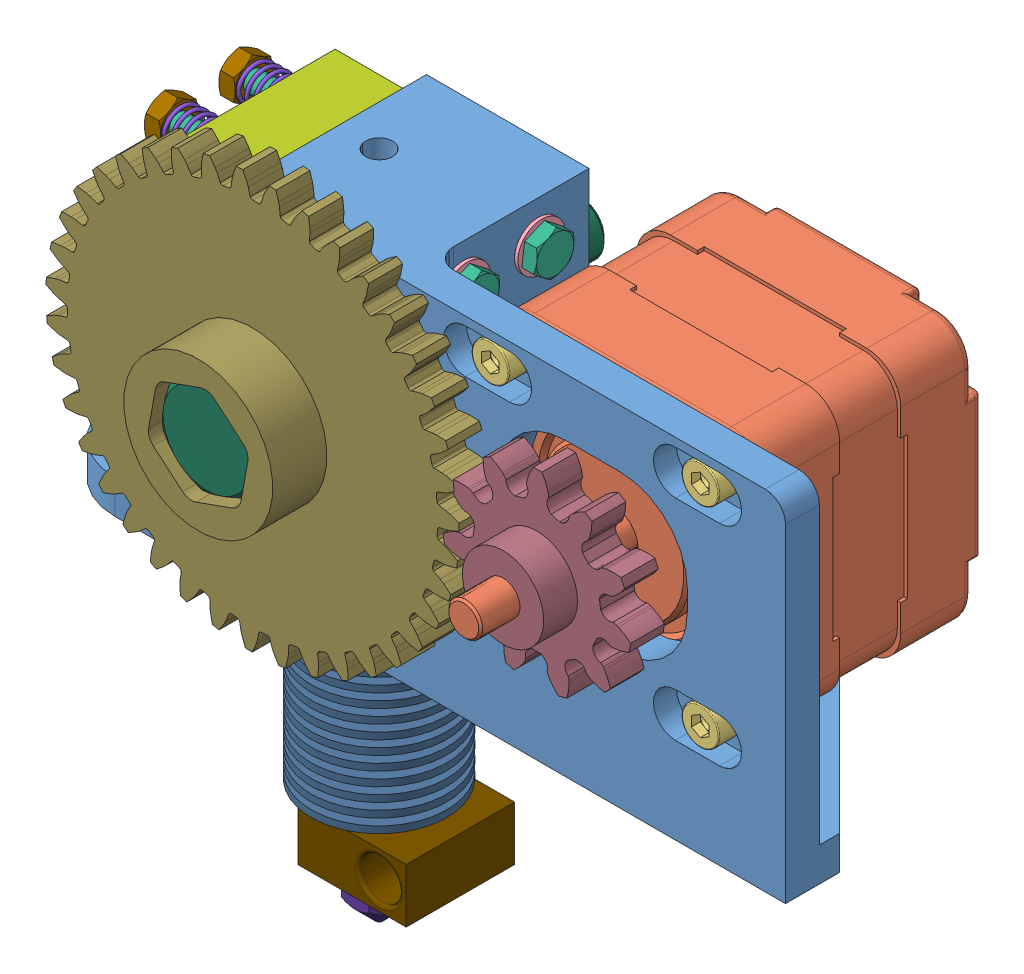
SolidWorks assembly X-Chariot, configuration Défaut. Lengths in mm.
Overall size (113.48 121.48 59.4).
80 component instances, 20 part files, 9 mates.
Components (placement in the parent):
- Extruder Body-1: Extruder Body [Défaut] at (51.5422 19.5906 0.8363) x (-1 0 0) z (0 0 -1) size (109 51.5 28)
- plain washer grade a_din_Washer DIN 125 - A 3.7-1: plain washer grade a_din_Washer DIN 125 - A 3.7 [Défaut] at (-44.9578 19.5906 7.8363) x (0 -1 0) z (0 0 1) size (0.5 8 8) (hidden)
- plain washer grade a_din_Washer DIN 125 - A 3.7-2: plain washer grade a_din_Washer DIN 125 - A 3.7 [Défaut] at (-44.9578 19.5906 21.8363) x (0 -1 0) z (0 0 1) size (0.5 8 8) (hidden)
- plain washer grade a_din_Washer DIN 125 - A 3.7-3: plain washer grade a_din_Washer DIN 125 - A 3.7 [Défaut] at (16.0422 19.5906 6.5863) x (0 -1 0) z (0 0 1) size (0.5 8 8) (hidden)
- plain washer grade a_din_Washer DIN 125 - A 3.7-4: plain washer grade a_din_Washer DIN 125 - A 3.7 [Défaut] at (16.0422 19.5906 18.0863) x (0 -1 0) z (0 0 1) size (0.5 8 8) (hidden)
- plain washer grade a_din_Washer DIN 125 - A 3.7-5: plain washer grade a_din_Washer DIN 125 - A 3.7 [Défaut] at (16.0422 3.5906 6.5863) x (0 1 0) z (0 0 1) size (0.5 8 8) (hidden)
- plain washer grade a_din_Washer DIN 125 - A 3.7-6: plain washer grade a_din_Washer DIN 125 - A 3.7 [Défaut] at (16.0422 3.5906 18.0863) x (0 1 0) z (0 0 1) size (0.5 8 8) (hidden)
- plain washer grade a_din_Washer DIN 125 - A 3.7-7: plain washer grade a_din_Washer DIN 125 - A 3.7 [Défaut] at (-44.9578 3.5906 7.8363) x (0 1 0) z (0 0 1) size (0.5 8 8) (hidden)
- plain washer grade a_din_Washer DIN 125 - A 3.7-8: plain washer grade a_din_Washer DIN 125 - A 3.7 [Défaut] at (-44.9578 3.5906 21.8363) x (0 1 0) z (0 0 1) size (0.5 8 8) (hidden)
- hex bolt gradeb_iso_ISO 4015 - M3 x 20 x 20-C-1: hex bolt gradeb_iso_ISO 4015 - M3 x 20 x 20-C [Défaut] at (-44.9578 22.0906 21.8363) x (0 -1 0) z (0 0 1) size (22 6.35 5.5) (hidden)
- hex bolt gradeb_iso_ISO 4015 - M3 x 20 x 20-C-2: hex bolt gradeb_iso_ISO 4015 - M3 x 20 x 20-C [Défaut] at (-44.9578 22.0906 7.8363) x (0 -1 0) z (0 0 1) size (22 6.35 5.5) (hidden)
- hex bolt gradeb_iso_ISO 4015 - M3 x 20 x 20-C-3: hex bolt gradeb_iso_ISO 4015 - M3 x 20 x 20-C [Défaut] at (16.0422 22.0906 6.5863) x (0 -1 0) z (0 0 1) size (22 6.35 5.5) (hidden)
- hex bolt gradeb_iso_ISO 4015 - M3 x 20 x 20-C-4: hex bolt gradeb_iso_ISO 4015 - M3 x 20 x 20-C [Défaut] at (16.0422 22.0906 18.0863) x (0 -1 0) z (0 0 1) size (22 6.35 5.5) (hidden)
- hex nut style 1 gradeab_iso_Hexagon Nut ISO - 4032 - M3 - D - C-1: hex nut style 1 gradeab_iso_Hexagon Nut ISO - 4032 - M3 - D - C [Défaut] at (-44.9578 0.6906 21.8363) x (1 0 0) z (0 -1 0) size (5.5 6.35 2.4) (hidden)
- hex nut style 1 gradeab_iso_Hexagon Nut ISO - 4032 - M3 - D - C-2: hex nut style 1 gradeab_iso_Hexagon Nut ISO - 4032 - M3 - D - C [Défaut] at (-44.9578 0.6906 7.8363) x (1 0 0) z (0 -1 0) size (5.5 6.35 2.4) (hidden)
- hex nut style 1 gradeab_iso_Hexagon Nut ISO - 4032 - M3 - D - C-3: hex nut style 1 gradeab_iso_Hexagon Nut ISO - 4032 - M3 - D - C [Défaut] at (16.0422 0.6906 6.5863) x (1 0 0) z (0 -1 0) size (5.5 6.35 2.4) (hidden)
- hex nut style 1 gradeab_iso_Hexagon Nut ISO - 4032 - M3 - D - C-4: hex nut style 1 gradeab_iso_Hexagon Nut ISO - 4032 - M3 - D - C [Défaut] at (16.0422 0.6906 18.0863) x (1 0 0) z (0 -1 0) size (5.5 6.35 2.4) (hidden)
- NEMA 17 Bipolar Stepper Motor-1: NEMA 17 Bipolar Stepper Motor [Défaut] at (23.0422 46.0906 7.3363) x (0 0 1) z (-1 0 0) size (57.01 39.01 39.01)
- socket head cap screw_iso_ISO 4762 M3 x 5 --- 5C-1: socket head cap screw_iso_ISO 4762 M3 x 5 --- 5C [Défaut] at (7.5422 61.5906 28.4363) x (0 0 -1) z (1 0 0) size (8 5.5 5.5)
- socket head cap screw_iso_ISO 4762 M3 x 5 --- 5C-2: socket head cap screw_iso_ISO 4762 M3 x 5 --- 5C [Défaut] at (38.5422 61.5906 28.4363) x (0 0 -1) z (1 0 0) size (8 5.5 5.5)
- socket head cap screw_iso_ISO 4762 M3 x 5 --- 5C-3: socket head cap screw_iso_ISO 4762 M3 x 5 --- 5C [Défaut] at (7.5422 30.5906 28.4363) x (0 0 -1) z (1 0 0) size (8 5.5 5.5)
- socket head cap screw_iso_ISO 4762 M3 x 5 --- 5C-4: socket head cap screw_iso_ISO 4762 M3 x 5 --- 5C [Défaut] at (38.5422 30.5906 28.4363) x (0 0 -1) z (1 0 0) size (8 5.5 5.5)
- plain washer grade a_din_Washer DIN 125 - A 3.2-1: plain washer grade a_din_Washer DIN 125 - A 3.2 [Défaut] at (-29.4578 60.0906 8.3363) size (0.5 7 7)
- plain washer grade a_din_Washer DIN 125 - A 3.2-2: plain washer grade a_din_Washer DIN 125 - A 3.2 [Défaut] at (-29.9578 60.0906 8.3363) size (0.5 7 7)
- plain washer grade a_din_Washer DIN 125 - A 3.2-3: plain washer grade a_din_Washer DIN 125 - A 3.2 [Défaut] at (-30.4578 60.0906 8.3363) size (0.5 7 7)
- plain washer grade a_din_Washer DIN 125 - A 3.2-4: plain washer grade a_din_Washer DIN 125 - A 3.2 [Défaut] at (-30.9578 60.0906 8.3363) x (1 0 0) z (0 0.451194 0.892426) size (0.5 7 7)
- Smooth Rod - f8x23-1: Smooth Rod - f8x23 [Défaut] at (-34.4578 46.0906 2.3363) x (1 0 0) z (0 -1 0) size (8 23 8)
- plain washer grade a_din_Washer DIN 125 - A 3.2-5: plain washer grade a_din_Washer DIN 125 - A 3.2 [Défaut] at (-5.4578 60.0906 19.3363) x (-1 0 0) z (0 0.924225 0.381849) size (0.5 7 7)
- plain washer grade a_din_Washer DIN 125 - A 3.2-6: plain washer grade a_din_Washer DIN 125 - A 3.2 [Défaut] at (-5.4578 60.0906 8.3363) x (-1 0 0) z (0 0.924225 0.381849) size (0.5 7 7)
- plain washer grade a_din_Washer DIN 125 - A 3.2-7: plain washer grade a_din_Washer DIN 125 - A 3.2 [Défaut] at (-5.4578 32.0906 8.3363) x (-1 0 0) z (0 0.924225 0.381849) size (0.5 7 7)
- plain washer grade a_din_Washer DIN 125 - A 3.2-8: plain washer grade a_din_Washer DIN 125 - A 3.2 [Défaut] at (-5.4578 32.0906 19.3363) x (-1 0 0) z (0 0.924225 0.381849) size (0.5 7 7)
- plain washer grade a_din_Washer DIN 125 - A 3.2-9: plain washer grade a_din_Washer DIN 125 - A 3.2 [Défaut] at (-29.4578 60.0906 19.3363) size (0.5 7 7)
- plain washer grade a_din_Washer DIN 125 - A 3.2-10: plain washer grade a_din_Washer DIN 125 - A 3.2 [Défaut] at (-29.4578 32.0906 19.3363) size (0.5 7 7)
- plain washer grade a_din_Washer DIN 125 - A 3.2-11: plain washer grade a_din_Washer DIN 125 - A 3.2 [Défaut] at (-29.4578 32.0906 8.3363) size (0.5 7 7)
- plain washer grade a_din_Washer DIN 125 - A 3.2-12: plain washer grade a_din_Washer DIN 125 - A 3.2 [Défaut] at (-29.9578 60.0906 19.3363) size (0.5 7 7)
- plain washer grade a_din_Washer DIN 125 - A 3.2-13: plain washer grade a_din_Washer DIN 125 - A 3.2 [Défaut] at (-30.4578 60.0906 19.3363) size (0.5 7 7)
- plain washer grade a_din_Washer DIN 125 - A 3.2-14: plain washer grade a_din_Washer DIN 125 - A 3.2 [Défaut] at (-29.9578 32.0906 19.3363) size (0.5 7 7)
- plain washer grade a_din_Washer DIN 125 - A 3.2-15: plain washer grade a_din_Washer DIN 125 - A 3.2 [Défaut] at (-30.4578 32.0906 19.3363) size (0.5 7 7)
- plain washer grade a_din_Washer DIN 125 - A 3.2-16: plain washer grade a_din_Washer DIN 125 - A 3.2 [Défaut] at (-30.9578 32.0906 19.3363) size (0.5 7 7)
- plain washer grade a_din_Washer DIN 125 - A 3.2-17: plain washer grade a_din_Washer DIN 125 - A 3.2 [Défaut] at (-29.9578 32.0906 8.3363) size (0.5 7 7)
- plain washer grade a_din_Washer DIN 125 - A 3.2-18: plain washer grade a_din_Washer DIN 125 - A 3.2 [Défaut] at (-30.4578 32.0906 8.3363) size (0.5 7 7)
- plain washer grade a_din_Washer DIN 125 - A 3.2-19: plain washer grade a_din_Washer DIN 125 - A 3.2 [Défaut] at (-30.9578 32.0906 8.3363) size (0.5 7 7)
- M3x45_ISO 4015 - M3 x 45 x 12-C-1: M3x45_ISO 4015 - M3 x 45 x 12-C [Défaut] at (-2.9578 60.0906 19.3363) x (-1 0 0) z (0 -0.924225 -0.381849) size (47 6.35 5.5)
- M3x45_ISO 4015 - M3 x 45 x 12-C-2: M3x45_ISO 4015 - M3 x 45 x 12-C [Défaut] at (-2.9578 32.0906 8.3363) x (-1 0 0) z (0 -0.924225 -0.381849) size (47 6.35 5.5)
- M3x45_ISO 4015 - M3 x 45 x 12-C-3: M3x45_ISO 4015 - M3 x 45 x 12-C [Défaut] at (-2.9578 32.0906 19.3363) x (-1 0 0) z (0 -0.924225 -0.381849) size (47 6.35 5.5)
- M3x45_ISO 4015 - M3 x 45 x 12-C-4: M3x45_ISO 4015 - M3 x 45 x 12-C [Défaut] at (-2.9578 60.0906 8.3363) x (-1 0 0) z (0 -0.924225 -0.381849) size (47 6.35 5.5)
- Idler Body-1: Idler Body [Défaut] at (-41.4578 28.0906 25.3363) x (0 0 -1) z (1 0 0) size (23 36 10)
- plain washer grade a_din_Washer DIN 125 - A 3.2-20: plain washer grade a_din_Washer DIN 125 - A 3.2 [Défaut] at (-30.9578 60.0906 19.3363) size (0.5 7 7)
- plain washer grade a_din_Washer DIN 125 - A 3.2-21: plain washer grade a_din_Washer DIN 125 - A 3.2 [Défaut] at (-41.4578 60.0906 8.3363) x (1 0 0) z (0 -0.022823 0.99974) size (0.5 7 7)
- plain washer grade a_din_Washer DIN 125 - A 3.2-22: plain washer grade a_din_Washer DIN 125 - A 3.2 [Défaut] at (-41.4578 60.0906 19.3363) size (0.5 7 7)
- plain washer grade a_din_Washer DIN 125 - A 3.2-23: plain washer grade a_din_Washer DIN 125 - A 3.2 [Défaut] at (-41.4578 32.0906 19.3363) size (0.5 7 7)
- plain washer grade a_din_Washer DIN 125 - A 3.2-24: plain washer grade a_din_Washer DIN 125 - A 3.2 [Défaut] at (-41.4578 32.0906 8.3363) size (0.5 7 7)
- Ballpoint Pen Spring - Extruder-1: Ballpoint Pen Spring - Extruder [Défaut] at (-42.2078 60.0906 8.3363) x (0 0.991476 -0.130286) z (0 0.130286 0.991476) size (5.53 5.52 5.5)
- Ballpoint Pen Spring - Extruder-2: Ballpoint Pen Spring - Extruder [Défaut] at (-42.2078 60.0906 19.3363) x (0 0.999694 0.024727) z (0 -0.024727 0.999694) size (5.53 5.52 5.5)
- Ballpoint Pen Spring - Extruder-3: Ballpoint Pen Spring - Extruder [Défaut] at (-42.2078 32.0906 8.3363) x (0 0.999047 -0.043643) z (0 0.043643 0.999047) size (5.53 5.52 5.5)
- Ballpoint Pen Spring - Extruder-4: Ballpoint Pen Spring - Extruder [Défaut] at (-42.2078 32.0906 19.3363) x (0 0.978843 -0.20461) z (0 0.20461 0.978843) size (5.53 5.52 5.5)
- hex nut style 1 gradeab_iso_Hexagon Nut ISO - 4032 - M3 - D - C-5: hex nut style 1 gradeab_iso_Hexagon Nut ISO - 4032 - M3 - D - C [Défaut] at (-47.4578 60.0906 8.3363) x (0 0 -1) z (1 0 0) size (5.5 6.35 2.4)
- hex nut style 1 gradeab_iso_Hexagon Nut ISO - 4032 - M3 - D - C-6: hex nut style 1 gradeab_iso_Hexagon Nut ISO - 4032 - M3 - D - C [Défaut] at (-47.4578 60.0906 19.3363) x (0 0 -1) z (1 0 0) size (5.5 6.35 2.4)
- hex nut style 1 gradeab_iso_Hexagon Nut ISO - 4032 - M3 - D - C-7: hex nut style 1 gradeab_iso_Hexagon Nut ISO - 4032 - M3 - D - C [Défaut] at (-46.9578 32.0906 8.3363) x (0 0.019138 -0.999817) z (1 0 0) size (5.5 6.35 2.4)
- hex nut style 1 gradeab_iso_Hexagon Nut ISO - 4032 - M3 - D - C-8: hex nut style 1 gradeab_iso_Hexagon Nut ISO - 4032 - M3 - D - C [Défaut] at (-47.4578 32.0906 19.3363) x (0 0.048448 -0.998826) z (1 0 0) size (5.5 6.35 2.4)
- Fourreau-1: Fourreau [Défaut] at (-23.4578 24.5906 13.8363) x (-1 0 0) z (0 0 -1) size (20 44 20)
- plain washer grade a_din_Washer DIN 125 - A 8.4-1: plain washer grade a_din_Washer DIN 125 - A 8.4 [Défaut] at (-18.9578 46.0906 28.8363) x (0 0 -1) z (0.999888 -0.014961 0) size (1.6 16 16)
- Large Gear-1: Large Gear [Défaut] at (-47.7391 12.1511 32.0363) x (-0.64677 -0.762685 0) z (0 0 1) size (60.98 60.94 13)
- plain washer grade a_din_Washer DIN 125 - A 8.4-2: plain washer grade a_din_Washer DIN 125 - A 8.4 [Défaut] at (-18.9578 46.0906 -0.7637) x (0 0 -1) z (0.808623 0.588327 0) size (1.6 16 16)
- Motor Shaft Pulley - Extruder-1: Motor Shaft Pulley - Extruder [Défaut] at (5.4114 54.4147 32.0363) x (0.336489 -0.941687 0) z (0 0 1) size (27.58 27.61 10)
- plain washer grade a_din_Washer DIN 125 - A 3.2-25: plain washer grade a_din_Washer DIN 125 - A 3.2 [Défaut] at (-29.4578 19.5906 28.8363) x (0 0 -1) z (1 0 0) size (0.5 7 7)
- plain washer grade a_din_Washer DIN 125 - A 3.2-26: plain washer grade a_din_Washer DIN 125 - A 3.2 [Défaut] at (-17.4578 19.5906 28.8363) x (0 0 -1) z (1 0 0) size (0.5 7 7)
- plain washer grade a_din_Washer DIN 125 - A 3.2-27: plain washer grade a_din_Washer DIN 125 - A 3.2 [Défaut] at (-29.4578 19.5906 0.8363) x (0 0 1) z (-1 0 0) size (0.5 7 7)
- plain washer grade a_din_Washer DIN 125 - A 3.2-28: plain washer grade a_din_Washer DIN 125 - A 3.2 [Défaut] at (-17.4578 19.5906 0.8363) x (0 0 1) z (-1 0 0) size (0.5 7 7)
- hex bolt gradeb_iso_ISO 4015 - M3 x 20 x 12-C-1: hex bolt gradeb_iso_ISO 4015 - M3 x 20 x 12-C [Défaut] at (-17.4578 19.5906 31.3363) x (0 0 -1) z (1 0 0) size (22 6.35 5.5)
- hex bolt gradeb_iso_ISO 4015 - M3 x 20 x 12-C-2: hex bolt gradeb_iso_ISO 4015 - M3 x 20 x 12-C [Défaut] at (-29.4578 19.5906 31.3363) x (0 0 -1) z (1 0 0) size (22 6.35 5.5)
- hex bolt gradeb_iso_ISO 4015 - M3 x 20 x 12-C-3: hex bolt gradeb_iso_ISO 4015 - M3 x 20 x 12-C [Défaut] at (-17.4578 19.5906 -1.6637) x (0 0 1) z (-1 0 0) size (22 6.35 5.5)
- hex bolt gradeb_iso_ISO 4015 - M3 x 20 x 12-C-4: hex bolt gradeb_iso_ISO 4015 - M3 x 20 x 12-C [Défaut] at (-29.4578 19.5906 -1.6637) x (0 0 1) z (-1 0 0) size (22 6.35 5.5)
- plain washer grade a_din_Washer DIN 125 - A 8.4-3: plain washer grade a_din_Washer DIN 125 - A 8.4 [Défaut] at (-18.9578 46.0906 30.4363) x (0 0 -1) z (0.820893 -0.571083 0) size (1.6 16 16)
- hex bolt gradeb_iso_ISO 4015 - M8 x 50 x 22-C-1: hex bolt gradeb_iso_ISO 4015 - M8 x 50 x 22-C [Défaut] at (-18.9578 46.0906 43.7363) x (0 0 -1) z (0.98389 -0.178776 0) size (55.3 15.01 13)
- radial ball bearing_68_skf_SKF - 608 - Full,DE,AC,Full_68-1: radial ball bearing_68_skf_SKF - 608 - Full,DE,AC,Full_68 [Défaut] at (-18.9578 46.0906 25.3363) x (0 0 1) z (-1 0 0) size (7.01 22 22)
- radial ball bearing_68_skf_SKF - 608 - Full,DE,AC,Full_68-2: radial ball bearing_68_skf_SKF - 608 - Full,DE,AC,Full_68 [Défaut] at (-18.9578 46.0906 4.3363) x (0 0 1) z (-1 0 0) size (7.01 22 22)
- radial ball bearing_68_skf_SKF - 608 - Full,DE,AC,Full_68-3: radial ball bearing_68_skf_SKF - 608 - Full,DE,AC,Full_68 [Défaut] at (-34.4578 46.0906 13.8363) x (0 0 -1) z (1 0 0) size (7.01 22 22)
- Buse-1: Buse [Défaut] at (-23.4578 -32.4094 13.8363) x (0 1 0) z (0 0 1) size (13 8.89 7)
- Support résistance-1: Support résistance [Défaut] at (-27.4578 -23.4094 5.8363) size (16 8 16)
Mates (geometry in assembly coordinates):
- Coaxiale14: concentric anti-aligned: cylinder of Extruder Body-1 through (-23.4578 24.5906 13.8363) axis (0 -1 0) radius 8; cylinder of Fourreau-1 through (-23.4578 33.7818 13.8363) axis (0 1 0) radius 8
- Coïncidente14: coincident anti-aligned: plane of Extruder Body-1 through (-23.4578 24.5906 13.8363) normal (0 -1 0); plane of Fourreau-1 through (-15.4578 24.5906 13.8363) normal (0 1 0)
- Coaxiale15: concentric anti-aligned: cylinder of Buse-1 through (-23.4578 -32.4094 13.8363) axis (0 -1 0) radius 3; cylinder of Fourreau-1 through (-23.4578 33.7818 13.8363) axis (0 1 0) radius 3
- Parallèle2: parallel aligned: plane of Buse-1 through (-23.4578 -32.4094 13.8363) normal (0 0 1); plane of assembly through (0 0 0) normal (0 0 1)
- Parallèle3: parallel anti-aligned: plane of Fourreau-1 through (-23.4578 24.5906 13.8363) normal (0 0 -1); plane of assembly through (0 0 0) normal (0 0 1)
- Coïncidente16: coincident anti-aligned: plane of Fourreau-1 through (-22.4578 -19.4094 13.8363) normal (0 -1 0); plane of Buse-1 through (-24.4078 -19.4094 13.8363) normal (0 1 0)
- Coaxiale16: concentric aligned: cylinder of Fourreau-1 through (-23.4578 33.7818 13.8363) axis (0 1 0) radius 3; cylinder of Support résistance-1 through (-23.4578 -23.4094 13.8363) axis (0 1 0) radius 2.5
- Distance1: distance = 1 mm anti-aligned: plane of Fourreau-1 through (-23.4578 -14.4094 13.8363) normal (0 -1 0); plane of Support résistance-1 through (-27.4578 -15.4094 21.8363) normal (0 1 0)
- Parallèle4: parallel aligned: plane of Buse-1 through (-25.4786 -34.4094 17.3363) normal (0 0 1); plane of Support résistance-1 through (-27.4578 -23.4094 21.8363) normal (0 0 1)
